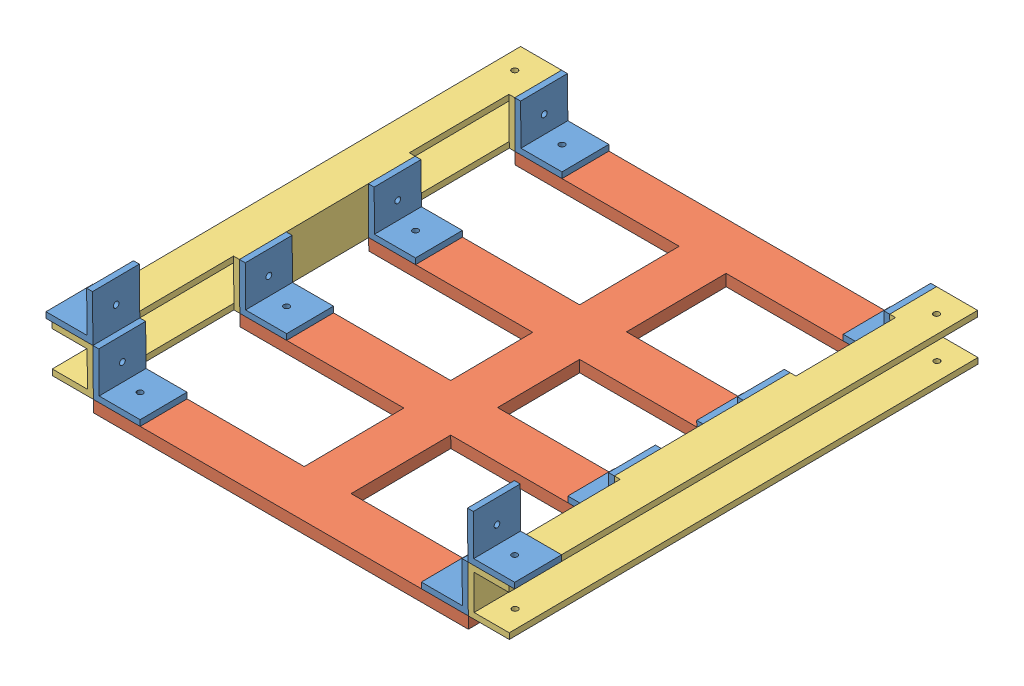
SolidWorks assembly 어셈블리1, configuration Default. Lengths in mm.
Overall size (254 57.37 254.49).
13 component instances, 3 part files, 24 mates.
Components (placement in the parent):
- 파트5-1: 파트5 [Default] at (22.3781 14.0116 20.3043) x (0 0.008727 -0.999962) z (-1 0 0) size (25.4 25.4 25.4)
- 파트6-1: 파트6 [Default] at (-79.2219 -6.0351 134.4337) x (1 0 0) z (0 0.999962 0.008727) size (203.2 254 6.35)
- 파트7-1: 파트7 [Default] at (33.4906 14.1224 7.6048) x (1 0 0) z (0 -0.008727 0.999962) size (22.23 25.4 254)
- 파트7-2: 파트7 [Default] at (-191.9344 11.9059 261.5951) x (-1 0 0) z (0 0.008727 -0.999962) size (22.23 25.4 254)
- 파트5-2: 파트5 [Default] at (22.3781 13.3189 99.6762) x (0 0.008727 -0.999962) z (-1 0 0) size (25.4 25.4 25.4)
- 파트5-3: 파트5 [Default] at (22.3781 12.7094 169.5236) x (0 0.008727 -0.999962) z (-1 0 0) size (25.4 25.4 25.4)
- 파트5-4: 파트5 [Default] at (22.3781 12.0167 248.8956) x (0 0.008727 -0.999962) z (-1 0 0) size (25.4 25.4 25.4)
- 파트5-5: 파트5 [Default] at (-180.8219 14.0116 20.3043) x (0 -0.008727 0.999962) z (1 0 0) size (25.4 25.4 25.4)
- 파트5-6: 파트5 [Default] at (-180.8219 13.3189 99.6762) x (0 -0.008727 0.999962) z (1 0 0) size (25.4 25.4 25.4)
- 파트5-7: 파트5 [Default] at (-180.8219 12.7094 169.5236) x (0 -0.008727 0.999962) z (1 0 0) size (25.4 25.4 25.4)
- 파트5-8: 파트5 [Default] at (-180.8219 12.0167 248.8956) x (0 -0.008727 0.999962) z (1 0 0) size (25.4 25.4 25.4)
- 파트5-9: 파트5 [Default] at (22.3781 37.4157 249.1172) x (0 -0.008727 0.999962) z (1 0 0) size (25.4 25.4 25.4)
- 파트5-10: 파트5 [Default] at (-180.8219 37.4157 249.1172) x (0 0.008727 -0.999962) z (-1 0 0) size (25.4 25.4 25.4)
Mates (geometry in assembly coordinates):
- 일치1: coincident anti-aligned: circle of 파트5-1; circle of 파트6-1
- 일치2: coincident anti-aligned: circle of 파트6-1; circle of 파트5-2
- 일치3: coincident anti-aligned: circle of 파트6-1; circle of 파트5-3
- 일치4: coincident anti-aligned: circle of 파트6-1; circle of 파트5-4
- 일치5: coincident anti-aligned: circle of 파트6-1; circle of 파트5-5
- 일치6: coincident anti-aligned: circle of 파트6-1; circle of 파트5-6
- 일치7: coincident anti-aligned: circle of 파트6-1; circle of 파트5-7
- 일치8: coincident anti-aligned: circle of 파트6-1; circle of 파트5-8
- 일치9: coincident aligned: circle of 파트7-2; circle of 파트5-8
- 일치12: coincident aligned: plane of 파트6-1 through (22.3781 -0.7937 261.4843) normal (0 -0.008727 0.999962); plane of 파트5-8 through (-177.6469 24.6054 261.7059) normal (0 -0.008727 0.999962)
- 일치13: coincident aligned: plane of 파트7-2 through (-203.0469 26.8219 7.7156) normal (0 0.999962 0.008727); plane of 파트5-8 through (-177.6469 24.6054 261.7059) normal (0 0.999962 0.008727)
- 일치15: coincident aligned: plane of 파트5-7 through (-177.6469 12.7094 169.5236) normal (1 0 0); plane of 파트5-8 through (-177.6469 12.0167 248.8956) normal (1 0 0)
- 일치16: coincident aligned: plane of 파트5-6 through (-177.6469 13.3189 99.6762) normal (1 0 0); plane of 파트5-7 through (-177.6469 12.7094 169.5236) normal (1 0 0)
- 일치17: coincident aligned: plane of 파트5-5 through (-177.6469 14.0116 20.3043) normal (1 0 0); plane of 파트5-6 through (-177.6469 13.3189 99.6762) normal (1 0 0)
- 일치18: coincident aligned: circle of 파트7-2; circle of 파트5-7
- 일치19: coincident aligned: circle of 파트7-2; circle of 파트5-6
- 일치20: coincident aligned: circle of 파트5-1; circle of 파트7-1
- 일치21: coincident aligned: circle of 파트7-1; circle of 파트5-2
- 일치22: coincident aligned: circle of 파트7-1; circle of 파트5-3
- 일치23: coincident aligned: circle of 파트7-1; circle of 파트5-4
- 일치24: coincident anti-aligned: circle of 파트7-1; circle of 파트5-9
- 일치25: coincident anti-aligned: circle of 파트7-2; circle of 파트5-10
- 일치26: coincident aligned: plane of 파트7-2 through (-191.9344 11.9059 261.5951) normal (0 -0.008727 0.999962); plane of 파트5-10 through (-183.9969 50.0044 261.9276) normal (0 -0.008727 0.999962)
- 일치27: coincident aligned: plane of 파트7-1 through (33.4906 11.9059 261.5951) normal (0 -0.008727 0.999962); plane of 파트5-9 through (25.5531 50.0044 261.9276) normal (0 -0.008727 0.999962)
